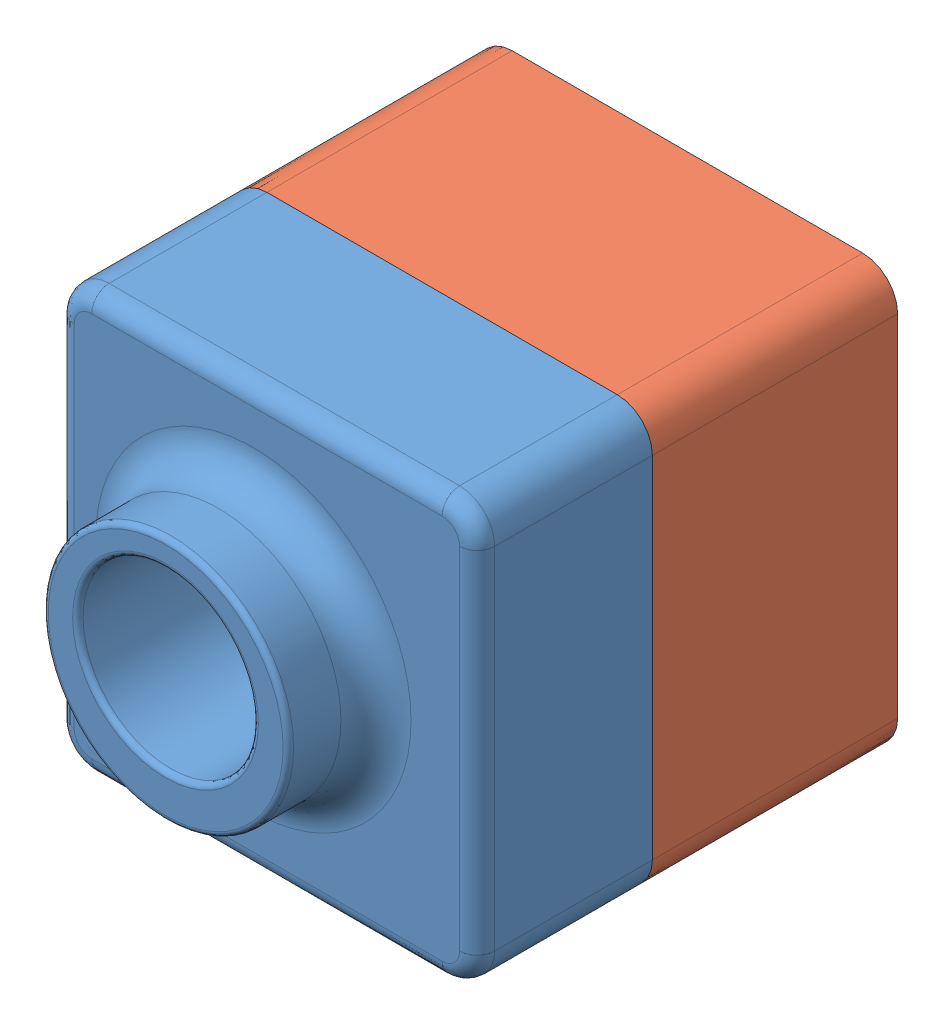
SolidWorks assembly Assem1, configuration Default. Lengths in mm.
Overall size (120 120 145).
2 component instances, 2 part files, 2 mates.
Components (placement in the parent):
- tutor1-1: tutor1 [Default] at (-22.903 0.0992 70.3855) size (120 120 75)
- tutor.2-1: tutor.2 [Default] at (-22.903 0.0992 0.3855) size (120 120 90)
Mates (geometry in assembly coordinates):
- Coincident10: coincident: line of tutor1-1 through (87.097 120.0992 70.3855) axis (-1 0 0); line of tutor.2-1 through (87.097 120.0992 70.3855) axis (-1 0 0)
- Coincident11: coincident aligned: line of tutor1-1 through (97.097 10.0992 70.3855) axis (0 1 0); line of tutor.2-1 through (97.097 10.0992 70.3855) axis (0 1 0)
